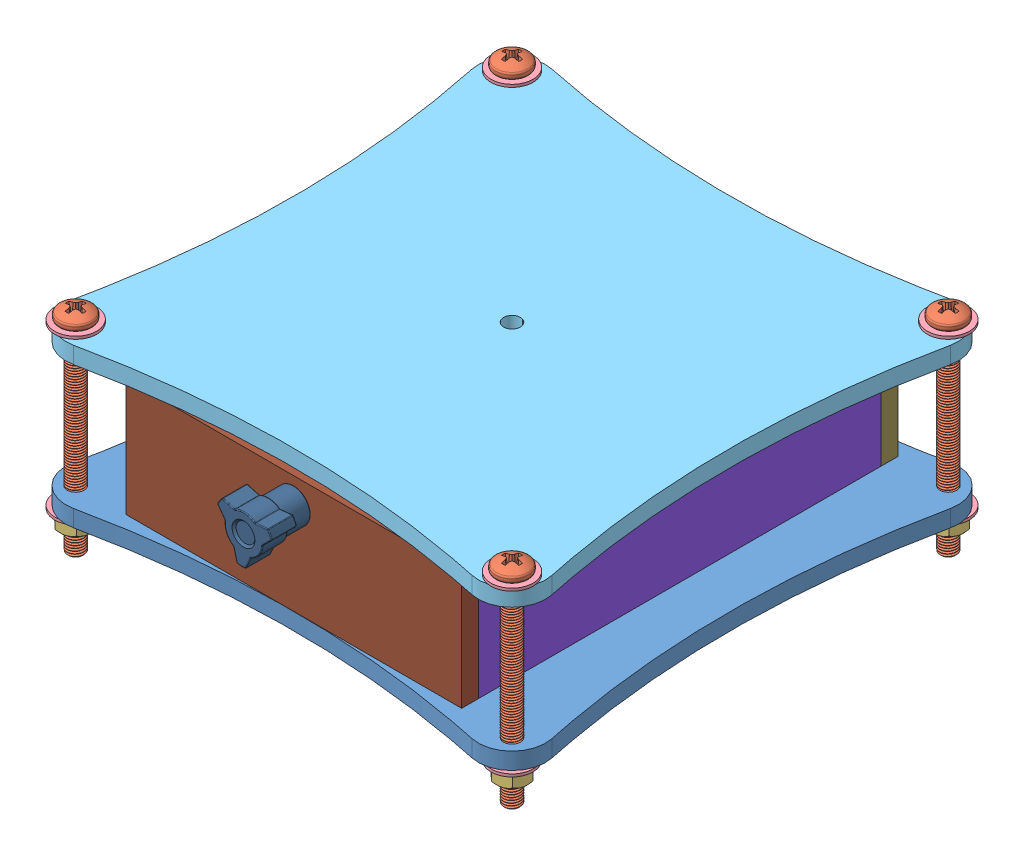
SolidWorks assembly splineBox, configuration Default. Lengths in mm.
Overall size (190.5 81.04 196.87).
32 component instances, 13 part files, 13 mates.
Components (placement in the parent):
- Part1^splineBox-1: Part1^splineBox [Default] at origin (virtual)
- MultiLightBox-1: MultiLightBox [Default] at (12.7795 81.2108 180.8537) size (190.5 6.35 190.5)
- quarterwashersubassembly-1: quarterwashersubassembly [Default] at (6.1018 31.9959 211.2727) x (1 0 0) z (0 1 0) size (15.88 16.32 171.96)
  - Quarter_TwentyEight91772A568-1: Quarter_TwentyEight91772A568 [91772A568] at (19.3777 43.119 33.8772) size (12.5 12.5 81.04)
  - nut93827A216-2: nut93827A216 [93827A216] at (19.3777 43.119 48.1989) x (0.972328 -0.233622 0) z (0.233622 0.972328 0) size (11.11 5.56 14.11)
  - washer90107A029-1: washer90107A029 [90107A029] at (19.3777 43.119 49.2149) size (15.88 15.88 1.02)
  - washer90107A029-2: washer90107A029 [90107A029] at (19.3777 43.119 110.0772) size (15.88 15.88 1.02)
- quarterwashersubassembly-2: quarterwashersubassembly [Default] at (6.1018 31.9959 46.1727) x (1 0 0) z (0 1 0) size (15.88 16.32 171.96)
  - Quarter_TwentyEight91772A568-1: Quarter_TwentyEight91772A568 [91772A568] at (19.3777 43.119 33.8772) size (12.5 12.5 81.04)
  - nut93827A216-2: nut93827A216 [93827A216] at (19.3777 43.119 48.1989) x (0.972328 -0.233622 0) z (0.233622 0.972328 0) size (11.11 5.56 14.11)
  - washer90107A029-1: washer90107A029 [90107A029] at (19.3777 43.119 49.2149) size (15.88 15.88 1.02)
  - washer90107A029-2: washer90107A029 [90107A029] at (19.3777 43.119 110.0772) size (15.88 15.88 1.02)
- quarterwashersubassembly-3: quarterwashersubassembly [Default] at (171.2018 31.9959 46.1727) x (1 0 0) z (0 1 0) size (15.88 16.32 171.96)
  - Quarter_TwentyEight91772A568-1: Quarter_TwentyEight91772A568 [91772A568] at (19.3777 43.119 33.8772) size (12.5 12.5 81.04)
  - nut93827A216-2: nut93827A216 [93827A216] at (19.3777 43.119 48.1989) x (0.972328 -0.233622 0) z (0.233622 0.972328 0) size (11.11 5.56 14.11)
  - washer90107A029-1: washer90107A029 [90107A029] at (19.3777 43.119 49.2149) size (15.88 15.88 1.02)
  - washer90107A029-2: washer90107A029 [90107A029] at (19.3777 43.119 110.0772) size (15.88 15.88 1.02)
- quarterwashersubassembly-4: quarterwashersubassembly [Default] at (171.2018 31.9959 211.2727) x (1 0 0) z (0 1 0) size (15.88 16.32 171.96)
  - Quarter_TwentyEight91772A568-1: Quarter_TwentyEight91772A568 [91772A568] at (19.3777 43.119 33.8772) size (12.5 12.5 81.04)
  - nut93827A216-2: nut93827A216 [93827A216] at (19.3777 43.119 48.1989) x (0.972328 -0.233622 0) z (0.233622 0.972328 0) size (11.11 5.56 14.11)
  - washer90107A029-1: washer90107A029 [90107A029] at (19.3777 43.119 49.2149) size (15.88 15.88 1.02)
  - washer90107A029-2: washer90107A029 [90107A029] at (19.3777 43.119 110.0772) size (15.88 15.88 1.02)
- MultiLightBoxTop-1: MultiLightBoxTop [Default] at (12.7795 134.7072 180.8537) size (190.5 6.35 190.5)
- traySubAssembly-2: traySubAssembly [Default] at (175.0905 267.316 236.9146) x (-1 0 0) z (0 -1 0) size (200.55 341.2 49.73)
  - trayBase-1: trayBase [Default] at (67.061 151.3109 148.0052) x (1 0 0) z (0 1 0) size (117.5 6.35 152.4)
  - trayFemaleSlot-2: trayFemaleSlot [Default] at (130.561 75.1109 179.7552) x (0 1 0) z (0 0 1) size (152.4 6.35 44.45)
  - trayFemaleSlotMirrored-1: trayFemaleSlotMirrored [Default] at (3.561 227.5109 179.7552) x (0 -1 0) z (0 0 1) size (152.4 6.35 44.45)
  - springNosePlunger3408A101-1: springNosePlunger3408A101 [3408A101] at (5.9359 100.5109 144.8302) x (0 -1 0) z (0 0 1) size (3.29 5.26 2.93)
  - springNosePlunger3408A101-2: springNosePlunger3408A101 [3408A101] at (128.1861 100.5109 144.8302) x (0 1 0) z (0 0 1) size (3.29 5.26 2.93)
  - Knob57715K360-1: Knob57715K360 [57715K36] at (67.061 75.1109 144.8302) x (0.573588 0 0.819144) z (0 -1 0) size (24.58 25.4 31.77)
  - backEnclosureWithHole-3: backEnclosureWithHole [Default] at (67.061 68.7609 157.5302) size (127 6.35 44.45)
  - backEnclosure-4: backEnclosure [Default] at (67.061 227.5109 157.5302) size (127 6.35 44.45)
Mates (geometry in assembly coordinates):
- Concentric1: concentric aligned: circle of MultiLightBox-1; circle of quarterwashersubassembly-1/Quarter_TwentyEight91772A568-1
- Coincident1: coincident anti-aligned: plane of MultiLightBox-1 through (12.7795 81.2108 180.8537) normal (0 -1 0); plane of quarterwashersubassembly-1/washer90107A029-1 through (25.4795 81.2108 168.1537) normal (0 1 0)
- Concentric2: concentric aligned: circle of MultiLightBox-1; circle of quarterwashersubassembly-2/washer90107A029-1
- Coincident2: coincident anti-aligned: plane of MultiLightBox-1 through (12.7795 81.2108 180.8537) normal (0 -1 0); plane of quarterwashersubassembly-2/washer90107A029-1 through (25.4795 81.2108 3.0537) normal (0 1 0)
- Concentric3: concentric aligned: circle of MultiLightBox-1; circle of quarterwashersubassembly-3/washer90107A029-2
- Coincident3: coincident anti-aligned: plane of MultiLightBox-1 through (12.7795 81.2108 180.8537) normal (0 -1 0); plane of quarterwashersubassembly-3/washer90107A029-1 through (190.5795 81.2108 3.0537) normal (0 1 0)
- Concentric4: concentric aligned: circle of MultiLightBox-1; circle of quarterwashersubassembly-4/washer90107A029-1
- Coincident4: coincident anti-aligned: plane of MultiLightBox-1 through (12.7795 81.2108 180.8537) normal (0 -1 0); plane of quarterwashersubassembly-4/washer90107A029-1 through (190.5795 81.2108 168.1537) normal (0 1 0)
- Concentric5: concentric aligned: circle of quarterwashersubassembly-1/washer90107A029-2; circle of MultiLightBoxTop-1
- Coincident5: coincident anti-aligned: plane of quarterwashersubassembly-1/washer90107A029-2 through (25.4795 141.0572 168.1537) normal (0 -1 0); plane of MultiLightBoxTop-1 through (12.7795 141.0572 180.8537) normal (0 1 0)
- Coincident6: coincident aligned: line of ? through (44.5295 87.5608 3.0537) axis (1 0 0); line of MultiLightBox-1 through (44.5295 87.5608 3.0537) axis (1 0 0)
- Coincident7: coincident anti-aligned: plane of MultiLightBox-1 through (12.7795 87.5608 180.8537) normal (0 1 0); plane of traySubAssembly-2/trayFemaleSlotMirrored-1 through (165.1795 87.5608 9.4037) normal (0 -1 0)
- Coincident8: coincident anti-aligned: line of MultiLightBox-1 through (171.5295 87.5608 173.7981) axis (0 0 -1); line of traySubAssembly-2/trayFemaleSlotMirrored-1 through (171.5295 87.5608 9.4037) axis (0 0 1)
